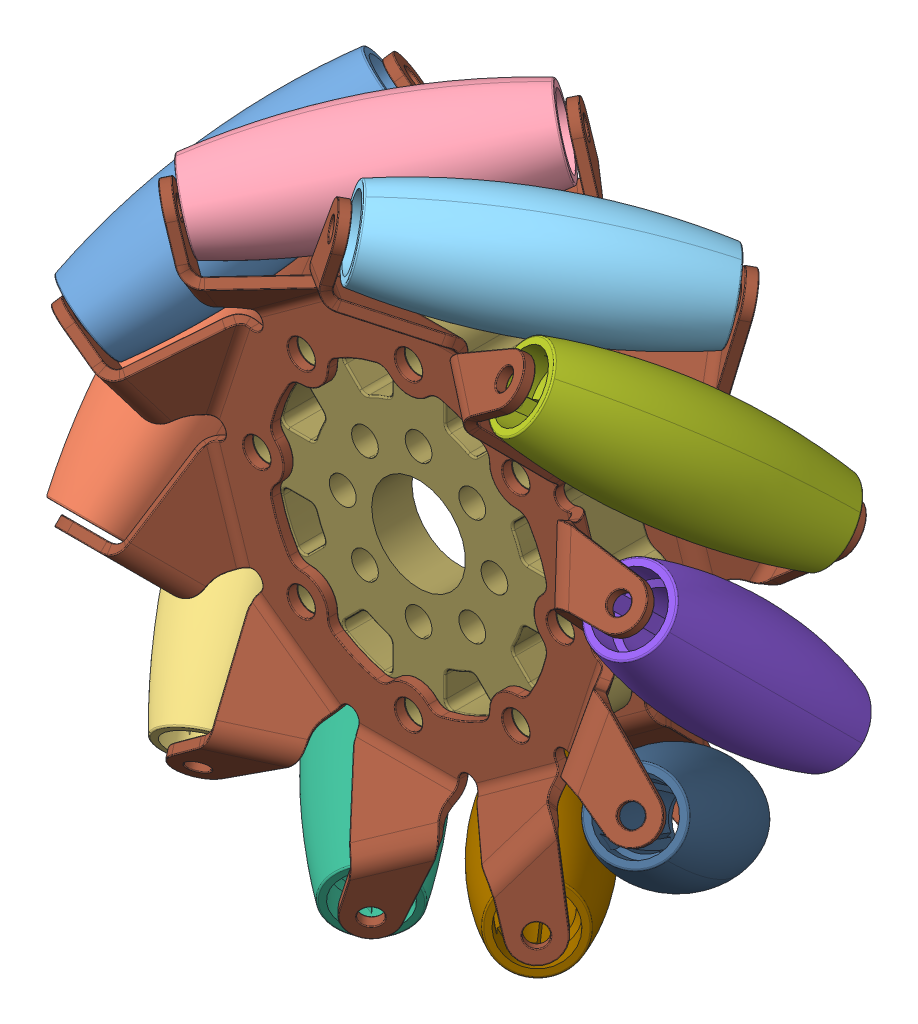
SolidWorks assembly Mecanum 1 GoBilda, configuration Valor predeterminado. Lengths in mm.
Overall size (134.34 133.52 55.59).
23 component instances, 12 part files, 0 mates.
Components (placement in the parent):
- 3606-XXXX-0096 roller assembly (3) _1_^Mecanum 1 GoBilda-1: 3606-XXXX-0096 roller assembly (3) _1_^Mecanum 1 GoBilda [Valor predeterminado] at origin size (54.98 49.77 55.59) (virtual)
  - 3606-XXXX-0096 roller cover(9)^3606-XXXX-0096 roller assembly (3) _1__Mecanum 1 GoBilda-1: 3606-XXXX-0096 roller cover(9)^3606-XXXX-0096 roller assembly (3) _1__Mecanum 1 GoBilda [Valor predeterminado] at (-64.4558 44.2167 53.9347) x (-0.426305 0.809267 -0.404167) z (-0.481681 0.175103 0.858675) size (32.9 29.25 38.52) (virtual)
- 3606-XXXX-0096 roller assembly (4) _1_^Mecanum 1 GoBilda-1: 3606-XXXX-0096 roller assembly (4) _1_^Mecanum 1 GoBilda [Valor predeterminado] at origin size (54.45 45.18 55.59) (virtual)
  - 3606-XXXX-0096 roller cover(2)^3606-XXXX-0096 roller assembly (4) _1__Mecanum 1 GoBilda-1: 3606-XXXX-0096 roller cover(2)^3606-XXXX-0096 roller assembly (4) _1__Mecanum 1 GoBilda [Valor predeterminado] at (-78.5873 29.8764 53.9347) x (-0.820563 0.404135 -0.404167) z (-0.492611 -0.141464 0.858675) size (32.9 29.25 38.52) (virtual)
- 3606-XXXX-0096 roller assembly (5) _1_^Mecanum 1 GoBilda-1: 3606-XXXX-0096 roller assembly (5) _1_^Mecanum 1 GoBilda [Valor predeterminado] at origin size (50.48 47.04 55.59) (virtual)
  - 3606-XXXX-0096 roller cover(8)^3606-XXXX-0096 roller assembly (5) _1__Mecanum 1 GoBilda-1: 3606-XXXX-0096 roller cover(8)^3606-XXXX-0096 roller assembly (5) _1__Mecanum 1 GoBilda [Valor predeterminado] at (-81.5909 9.9685 53.9347) x (-0.901394 -0.155363 -0.404167) z (-0.315381 -0.403996 0.858675) size (32.9 29.25 38.52) (virtual)
- 3606-XXXX-0096 roller assembly (2) _1_^Mecanum 1 GoBilda-1: 3606-XXXX-0096 roller assembly (2) _1_^Mecanum 1 GoBilda [Valor predeterminado] at origin size (43.11 46.25 55.59) (virtual)
  - 3606-XXXX-0096 roller cover(6)^3606-XXXX-0096 roller assembly (2) _1__Mecanum 1 GoBilda-1: 3606-XXXX-0096 roller cover(6)^3606-XXXX-0096 roller assembly (2) _1__Mecanum 1 GoBilda [Valor predeterminado] at (-44.5942 47.512 53.9347) x (0.130787 0.905286 -0.404167) z (-0.286765 0.424787 0.858675) size (32.9 29.25 38.52) (virtual)
- 3606-XXXX-0096 roller assembly (1) _1_^Mecanum 1 GoBilda-1: 3606-XXXX-0096 roller assembly (1) _1_^Mecanum 1 GoBilda [Valor predeterminado] at origin size (44.19 57.53 55.59) (virtual)
  - 3606-XXXX-0096 roller cover(3)^3606-XXXX-0096 roller assembly (1) _1__Mecanum 1 GoBilda-1: 3606-XXXX-0096 roller cover(3)^3606-XXXX-0096 roller assembly (1) _1__Mecanum 1 GoBilda [Valor predeterminado] at (-26.5889 38.5036 53.9347) x (0.637923 0.655517 -0.404167) z (0.017685 0.512216 0.858675) size (32.9 29.25 38.52) (virtual)
- 3606-XXXX-0096 roller assembly (6) _1_^Mecanum 1 GoBilda-1: 3606-XXXX-0096 roller assembly (6) _1_^Mecanum 1 GoBilda [Valor predeterminado] at origin size (44.19 57.53 55.59) (virtual)
  - 3606-XXXX-0096 roller cover(4)^3606-XXXX-0096 roller assembly (6) _1__Mecanum 1 GoBilda-1: 3606-XXXX-0096 roller cover(4)^3606-XXXX-0096 roller assembly (6) _1__Mecanum 1 GoBilda [Valor predeterminado] at (-72.3193 -7.9027 53.9347) x (-0.637923 -0.655517 -0.404167) z (-0.017685 -0.512216 0.858675) size (32.9 29.25 38.52) (virtual)
- 3606-XXXX-0096 roller assembly _1_^Mecanum 1 GoBilda-1: 3606-XXXX-0096 roller assembly _1_^Mecanum 1 GoBilda [Valor predeterminado] at origin size (50.48 47.04 55.59) (virtual)
  - 3606-XXXX-0096 roller cover(7)^3606-XXXX-0096 roller assembly _1__Mecanum 1 GoBilda-1: 3606-XXXX-0096 roller cover(7)^3606-XXXX-0096 roller assembly _1__Mecanum 1 GoBilda [Valor predeterminado] at (-17.3173 20.6323 53.9347) x (0.901394 0.155363 -0.404167) z (0.315381 0.403996 0.858675) size (32.9 29.25 38.52) (virtual)
- 3606-XXXX-0096 roller assembly (9) _1_^Mecanum 1 GoBilda-1: 3606-XXXX-0096 roller assembly (9) _1_^Mecanum 1 GoBilda [Valor predeterminado] at origin size (54.45 45.18 55.59) (virtual)
  - 3606-XXXX-0096 roller cover(5)^3606-XXXX-0096 roller assembly (9) _1__Mecanum 1 GoBilda-1: 3606-XXXX-0096 roller cover(5)^3606-XXXX-0096 roller assembly (9) _1__Mecanum 1 GoBilda [Valor predeterminado] at (-20.3209 0.7245 53.9347) x (0.820563 -0.404135 -0.404167) z (0.492611 0.141464 0.858675) size (32.9 29.25 38.52) (virtual)
- 3606-XXXX-0096 roller assembly (7) _1_^Mecanum 1 GoBilda-1: 3606-XXXX-0096 roller assembly (7) _1_^Mecanum 1 GoBilda [Valor predeterminado] at origin size (43.11 46.25 55.59) (virtual)
  - 3606-XXXX-0096 roller cover^3606-XXXX-0096 roller assembly (7) _1__Mecanum 1 GoBilda-1: 3606-XXXX-0096 roller cover^3606-XXXX-0096 roller assembly (7) _1__Mecanum 1 GoBilda [Valor predeterminado] at (-54.314 -16.9111 53.9347) x (-0.130787 -0.905286 -0.404167) z (0.286765 -0.424787 0.858675) size (32.9 29.25 38.52) (virtual)
- 3606-XXXX-0096 roller assembly (8) _1_^Mecanum 1 GoBilda-1: 3606-XXXX-0096 roller assembly (8) _1_^Mecanum 1 GoBilda [Valor predeterminado] at origin size (54.98 49.77 55.59) (virtual)
  - 3606-XXXX-0096 roller cover(10)^3606-XXXX-0096 roller assembly (8) _1__Mecanum 1 GoBilda-1: 3606-XXXX-0096 roller cover(10)^3606-XXXX-0096 roller assembly (8) _1__Mecanum 1 GoBilda [Valor predeterminado] at (-34.4523 -13.6158 53.9347) x (0.426305 -0.809267 -0.404167) z (0.481681 -0.175103 0.858675) size (32.9 29.25 38.52) (virtual)
- 3606-0000-0096 left slant side plate^Mecanum 1 GoBilda-1: 3606-0000-0096 left slant side plate^Mecanum 1 GoBilda [Valor predeterminado] at (-49.4541 15.3004 9.2101) size (89.82 92.69 13.15) (virtual)
- 3606-0000-0096 left slant side plate^Mecanum 1 GoBilda-2: 3606-0000-0096 left slant side plate^Mecanum 1 GoBilda [Valor predeterminado] at (-49.4541 15.3004 -2.7899) x (-1 0 0) z (0 0 -1) size (89.82 92.69 13.15) (virtual)
- 3606-XXXX-0096 core^Mecanum 1 GoBilda-1: 3606-XXXX-0096 core^Mecanum 1 GoBilda [Valor predeterminado] at (-49.4541 15.3004 -2.7899) size (53.25 53.25 12) (virtual)
